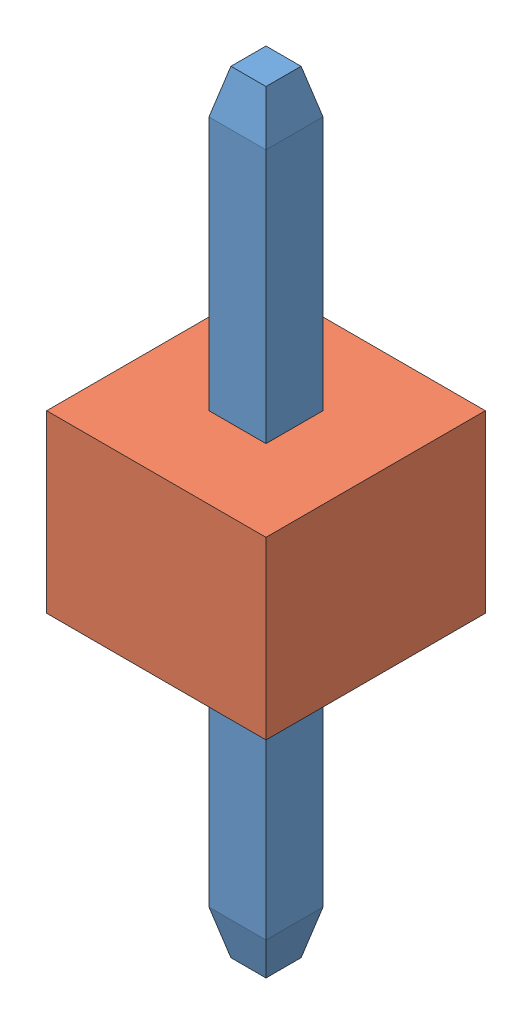
SolidWorks assembly Jumper, configuration Male-male. Lengths in mm.
Overall size (2.5 18.8 2.5).
2 component instances, 2 part files, 3 mates.
Components (placement in the parent):
- Pin-1: Pin [Default] at origin size (0.65 18.8 0.65)
- Socket-1: Socket [Blok] at origin size (2.5 2 2.5)
Mates (geometry in assembly coordinates):
- Coincident1: coincident anti-aligned: plane of Pin-1 through (-0.325 9.4 0.325) normal (0 0 1); plane of Socket-1 through (0.325 -1.001 0.325) normal (0 0 -1)
- Coincident2: coincident anti-aligned: plane of Pin-1 through (-0.325 9.4 0.325) normal (-1 0 0); plane of Socket-1 through (-0.325 -1.001 0.325) normal (1 0 0)
- Coincident3: coincident aligned: plane of Pin-1 through (0 0 0) normal (0 1 0); plane of Socket-1 through (0 0 0) normal (0 1 0)
